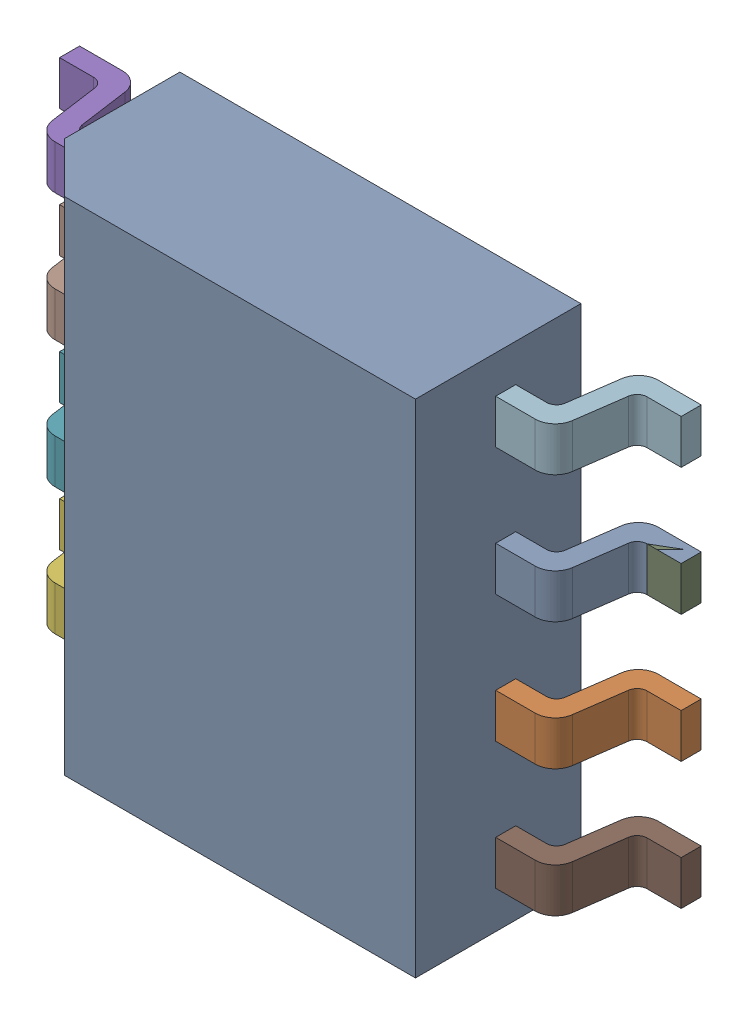
SolidWorks assembly DA1, configuration По умолчанию. Lengths in mm.
Overall size (6.2 5 1.75).
16 component instances, 2 part files, 0 mates.
Components (placement in the parent):
- User_Library-HSOP8-1: User_Library-HSOP8 [По умолчанию] at (38.75 16 0) x (-1 0 0) z (0 1 0) size (6.2 1.75 5)
  - User_Library-HSOP8_part_hsop8_____________-1: User_Library-HSOP8_part_hsop8_____________ [По умолчанию] at origin size (4 1.75 5)
  - User_Library-HSOP8_Assy_fuss_hsop8_____________-1: User_Library-HSOP8_Assy_fuss_hsop8_____________ [По умолчанию] at (2 0 0) size (1.1 0.95 4.25)
    - User_Library-HSOP8_Fuss_hsop8_____________-1: User_Library-HSOP8_Fuss_hsop8_____________ [По умолчанию] at (0 0 -0.635) size (1.1 0.95 0.44)
    - User_Library-HSOP8_Fuss_hsop8_____________-2: User_Library-HSOP8_Fuss_hsop8_____________ [По умолчанию] at (0 0 0.635) size (1.1 0.95 0.44)
    - User_Library-HSOP8_Fuss_hsop8_____________-3: User_Library-HSOP8_Fuss_hsop8_____________ [По умолчанию] at (0 0 1.905) size (1.1 0.95 0.44)
    - User_Library-HSOP8_Fuss_hsop8_____________-4: User_Library-HSOP8_Fuss_hsop8_____________ [По умолчанию] at (0 0 -1.905) size (1.1 0.95 0.44)
    - User_Library-HSOP8_Fuss_hsop8_____________-5: User_Library-HSOP8_Fuss_hsop8_____________ [По умолчанию] at (0 0 -0.635) size (1.1 0.95 0.44)
    - User_Library-HSOP8_Fuss_hsop8_____________-6: User_Library-HSOP8_Fuss_hsop8_____________ [По умолчанию] at (0 0 0.635) size (1.1 0.95 0.44)
  - User_Library-HSOP8_Assy_fuss_hsop8_____________-2: User_Library-HSOP8_Assy_fuss_hsop8_____________ [По умолчанию] at (-2 0 0) x (-1 0 0) z (0 0 -1) size (1.1 0.95 4.25)
    - User_Library-HSOP8_Fuss_hsop8_____________-1: User_Library-HSOP8_Fuss_hsop8_____________ [По умолчанию] at (0 0 -0.635) size (1.1 0.95 0.44)
    - User_Library-HSOP8_Fuss_hsop8_____________-2: User_Library-HSOP8_Fuss_hsop8_____________ [По умолчанию] at (0 0 0.635) size (1.1 0.95 0.44)
    - User_Library-HSOP8_Fuss_hsop8_____________-3: User_Library-HSOP8_Fuss_hsop8_____________ [По умолчанию] at (0 0 1.905) size (1.1 0.95 0.44)
    - User_Library-HSOP8_Fuss_hsop8_____________-4: User_Library-HSOP8_Fuss_hsop8_____________ [По умолчанию] at (0 0 -1.905) size (1.1 0.95 0.44)
    - User_Library-HSOP8_Fuss_hsop8_____________-5: User_Library-HSOP8_Fuss_hsop8_____________ [По умолчанию] at (0 0 -0.635) size (1.1 0.95 0.44)
    - User_Library-HSOP8_Fuss_hsop8_____________-6: User_Library-HSOP8_Fuss_hsop8_____________ [По умолчанию] at (0 0 0.635) size (1.1 0.95 0.44)
